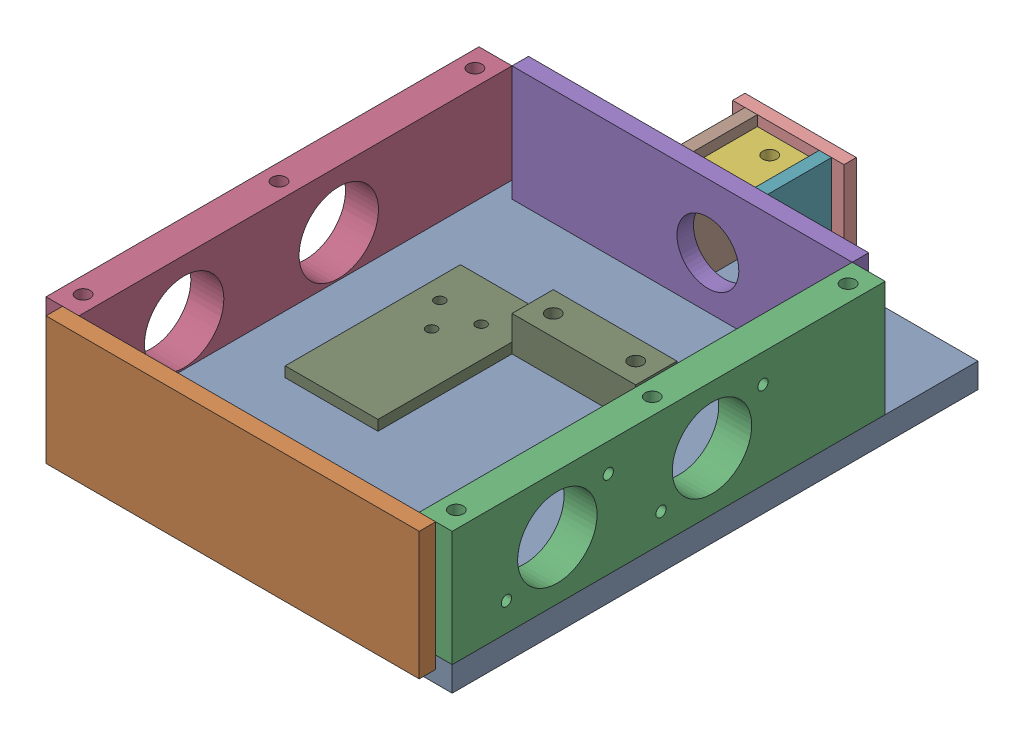
SolidWorks assembly g1_3_1_1_8_1_af0_1, configuration 默认. Lengths in mm.
Overall size (197 68 263).
11 component instances, 10 part files, 0 mates.
Components (placement in the parent):
- g1_3_1_1_8_1-3_af1_1-1: g1_3_1_1_8_1-3_af1_1 [默认] at origin size (197 12 255)
- g1_3_1_1_8_1-1_1-1: g1_3_1_1_8_1-1_1 [默认] at (0 37 127.5) x (1 0 0) z (0 -1 0) size (181 8 62)
- g1_3_1_1_8_1-2_af1_1-1: g1_3_1_1_8_1-2_af1_1 [默认] at (98.5 40 22.5) x (0 1 0) z (0 0 1) size (56 16 210)
- g1_3_1_1_8_1-2_af0_1-1: g1_3_1_1_8_1-2_af0_1 [默认] at (-98.5 40 22.5) x (0 1 0) z (0 0 -1) size (56 16 210)
- g1_3_1_1_8_1-5_1-1: g1_3_1_1_8_1-5_1 [默认] at (0 40 -82.5) x (1 0 0) z (0 1 0) size (165 8 56)
- g1_3_1_1_8_1-7_af0_1-1: g1_3_1_1_8_1-7_af0_1 [默认] at (12.5 57 -106) size (30 6 31)
- g1_3_1_1_8_1-6_1-1: g1_3_1_1_8_1-6_1 [默认] at (27.5 40 -106) x (0 1 0) z (0 0 -1) size (56 6 31)
- g1_3_1_1_8_1-6_1-2: g1_3_1_1_8_1-6_1 [默认] at (-8.5 40 -106) x (0 1 0) z (0 0 -1) size (56 6 31)
- g1_3_1_1_8_1-4_af1_1-1: g1_3_1_1_8_1-4_af1_1 [默认] at (-10 12 5) size (105 17 85)
- g1_3_1_1_8_1-8_af0_1-1: g1_3_1_1_8_1-8_af0_1 [默认] at (12.5 40 -127.5) x (0 1 0) z (1 0 0) size (56 6 54)
- g1_3_1_1_8_1_af0_more_1-1: g1_3_1_1_8_1_af0_more_1 [默认] at origin size (197 61 238)
